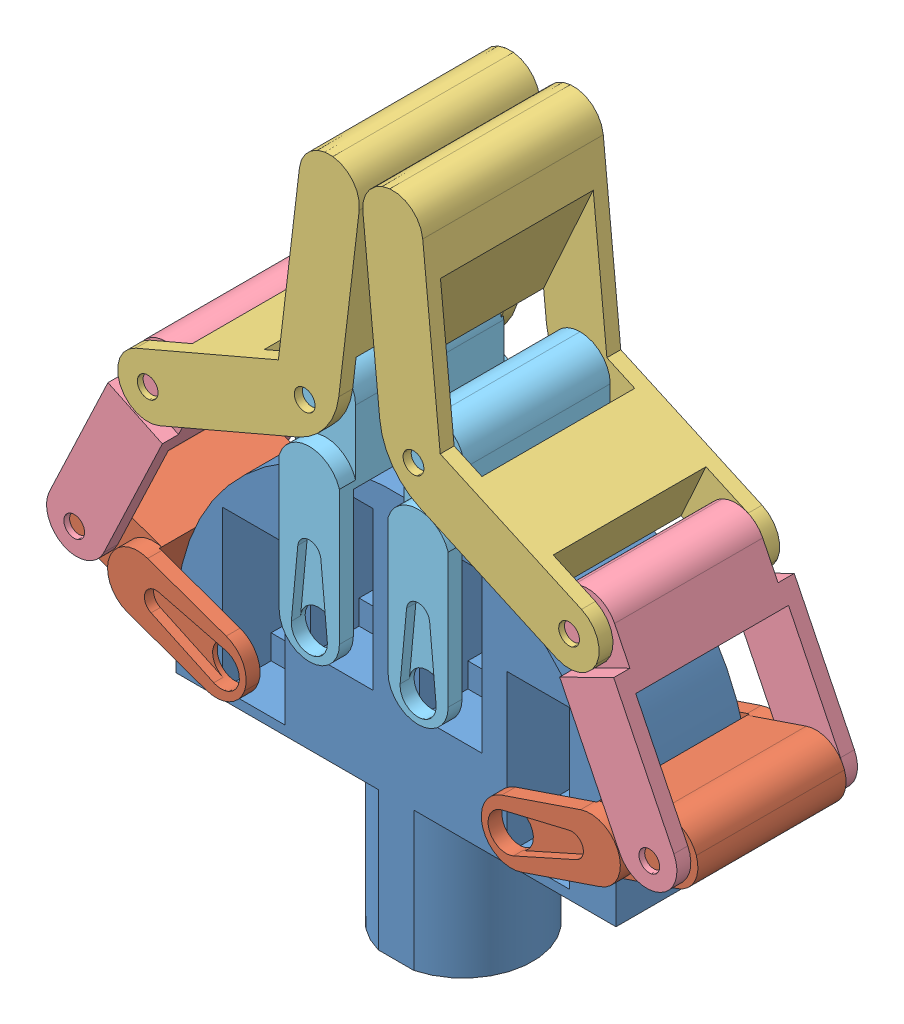
SolidWorks assembly montagem, configuration Valor predeterminado. Lengths in mm.
Overall size (140.77 155.97 40).
9 component instances, 5 part files, 24 mates.
Components (placement in the parent):
- palma-1: palma [Valor predeterminado] at (-5.7206 -27.6488 81.5) size (95 87.5 32)
- finger1_2x-1: finger1_2x [Valor predeterminado] at (-29.3023 -20.5523 78.5) x (0 0 1) z (-0.335585 -0.94201 0) size (39 45 13)
- finger1_2x-2: finger1_2x [Valor predeterminado] at (22.1082 -32.7564 78.5) x (0 0 1) z (-0.32174 0.946828 0) size (39 45 13)
- finger3_2x-1: finger3_2x [Valor predeterminado] at (-18.2017 31.6383 79.5) x (0.993448 -0.114286 0) z (0 0 1) size (45.5 73.75 39)
- finger3_2x-2: finger3_2x [Valor predeterminado] at (6.6862 31.6242 118.5) x (-0.995554 -0.094195 0) z (0 0 -1) size (45.5 73.75 39)
- finger4_2x-1: finger4_2x [Valor predeterminado] at (-75.8925 -15.7535 118) x (0 0 -1) z (0.903545 -0.428494 0) size (39 50 13)
- finger4_2x-2: finger4_2x [Valor predeterminado] at (64.6373 -16.1041 79) x (0 0 1) z (-0.897728 -0.440551 0) size (39 50 13)
- finger2_2x-1: finger2_2x [Valor predeterminado] at (-10.9706 -14.1928 78.5) x (0 0 1) z (-1 0 0) size (39 56 13)
- finger2_2x-2: finger2_2x [Valor predeterminado] at (12.5294 -14.1928 78.5) x (0 0 1) z (-1 0 0) size (39 56 13)
Mates (geometry in assembly coordinates):
- Coincident1: coincident anti-aligned: plane of palma-1 through (-5.7206 -27.6488 81.5) normal (0 0 -1); plane of finger1_2x-1 through (-33.6649 -32.7984 81.5) normal (0 0 1)
- Concentric1: concentric anti-aligned: circle of palma-1; circle of finger1_2x-1
- Coincident2: coincident anti-aligned: plane of palma-1 through (-5.7206 -27.6488 81.5) normal (0 0 -1); plane of finger1_2x-2 through (17.9256 -20.4477 81.5) normal (0 0 1)
- Concentric2: concentric anti-aligned: circle of palma-1; circle of finger1_2x-2
- Coincident3: coincident anti-aligned: plane of palma-1 through (-5.7206 -27.6488 81.5) normal (0 0 -1); plane of ? through (-0.545 -14.1001 81.5) normal (0 0 1)
- Coincident4: coincident anti-aligned: plane of palma-1 through (-5.7206 -27.6488 81.5) normal (0 0 -1); plane of ? through (-24.1017 -14.0276 81.5) normal (0 0 1)
- Concentric3: concentric anti-aligned: circle of palma-1; circle of ?
- Concentric4: concentric anti-aligned: circle of palma-1; circle of ?
- Coincident5: coincident anti-aligned: plane of finger1_2x-1 through (-62.8673 -22.3953 82) normal (0 0 -1); plane of finger4_2x-1 through (-50.4346 7.5896 82) normal (0 0 1)
- Concentric5: concentric aligned: circle of finger1_2x-1; circle of finger4_2x-1
- Coincident6: coincident anti-aligned: plane of finger1_2x-2 through (47.2772 -10.4737 82) normal (0 0 -1); plane of finger4_2x-2 through (52.9668 -21.8312 82) normal (0 0 1)
- Concentric6: concentric aligned: circle of finger1_2x-2; circle of finger4_2x-2
- Coincident7: coincident anti-aligned: plane of finger3_2x-2 through (71.4712 74.6068 82.5) normal (0 0 1); plane of finger4_2x-2 through (37.107 10.487 82.5) normal (0 0 -1)
- Concentric7: concentric aligned: circle of finger3_2x-2; circle of finger4_2x-2
- Coincident8: coincident anti-aligned: plane of finger3_2x-1 through (-82.1053 75.9207 82.5) normal (0 0 1); plane of finger4_2x-1 through (-42.7217 23.8534 82.5) normal (0 0 -1)
- Concentric8: concentric aligned: circle of finger3_2x-1; circle of finger4_2x-1
- Concentric9: concentric aligned: circle of ?; circle of finger3_2x-2
- Concentric10: concentric aligned: circle of ?; circle of finger3_2x-1
- Concentric11: concentric anti-aligned: circle of palma-1; circle of finger2_2x-1
- Coincident9: coincident aligned: plane of palma-1 through (-17.4706 -8.8988 78.5) normal (0 0 -1); plane of finger2_2x-1 through (-23.9706 -14.1928 78.5) normal (0 0 -1)
- Coincident10: coincident aligned: plane of palma-1 through (6.0294 -8.8988 78.5) normal (0 0 -1); plane of finger2_2x-2 through (-0.4706 -14.1928 78.5) normal (0 0 -1)
- Concentric12: concentric anti-aligned: circle of palma-1; circle of finger2_2x-2
- Concentric13: concentric aligned: circle of finger3_2x-2; circle of finger2_2x-2
- Concentric14: concentric anti-aligned: circle of finger3_2x-1; circle of finger2_2x-1
